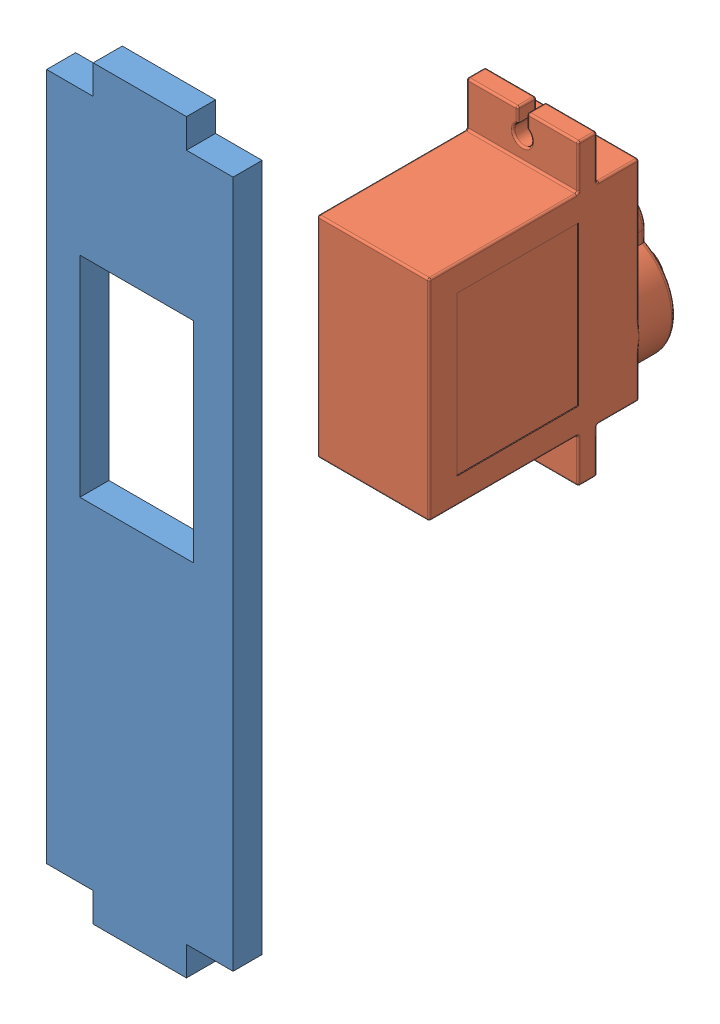
SolidWorks assembly arm thing for bobobobobobobooxoxoxo, configuration Default. Lengths in mm.
Overall size (59.03 100.63 29).
2 component instances, 2 part files, 2 mates.
Components (placement in the parent):
- Servo Holder-1: Servo Holder [Default] at (30.6724 45.6481 58.3297) size (20 80 3.12)
- Micro Servo FS90R Continuous-1: Micro Servo FS90R Continuous [Valor predeterminado] at (73.7044 90.279 63.4497) x (0 1 0) z (-1 0 0) size (32 29 12)
Mates (geometry in assembly coordinates):
- Parallel1: parallel anti-aligned: plane of Servo Holder-1 through (40.6724 5.6481 61.4497) normal (1 0 0); plane of Micro Servo FS90R Continuous-1 through (67.7044 79.029 79.4497) normal (-1 0 0)
- Coincident3: coincident anti-aligned: plane of Servo Holder-1 through (30.6724 45.6481 61.4497) normal (0 0 1); plane of Micro Servo FS90R Continuous-1 through (73.7044 103.904 61.4497) normal (0 0 -1)
